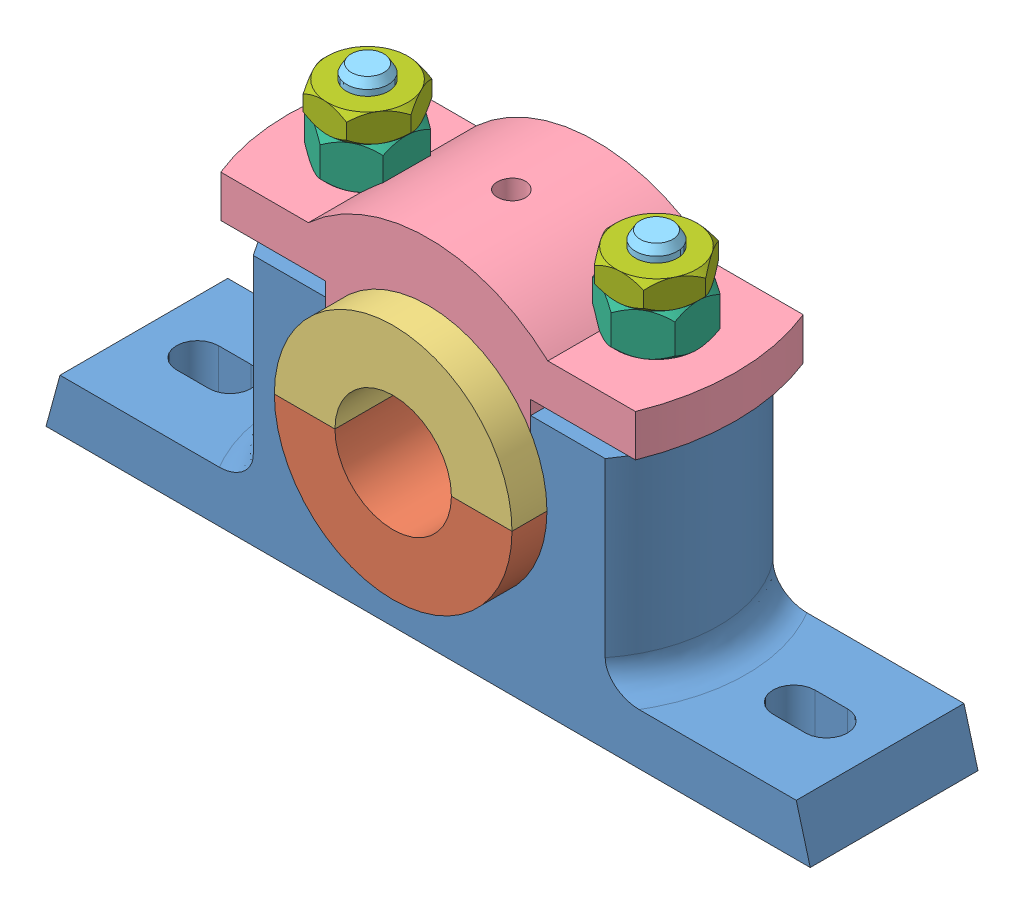
SolidWorks assembly Assem1, configuration Default. Lengths in mm.
Overall size (164 84 51).
10 component instances, 7 part files, 13 mates.
Components (placement in the parent):
- Part1-2: Part1 [Default] at (47.1008 133.5822 81.464) size (164 54 36)
- part3 - Copy-4: part3 - Copy [Default] at (47.1008 133.5822 99.464) x (0 -1 0) z (-1 0 0) size (25.5 51 51)
- part3-3: part3 [Default] at (47.1008 133.5822 99.464) x (0 1 0) z (-1 0 0) size (25.5 51 51)
- PART2-3: PART2 [Default] at (47.1008 133.5822 99.464) size (96 32 36)
- bolt-1: bolt [Default] at (16.1008 179.5822 99.464) x (-0.397328 0 0.917677) z (0 -1 0) size (19 19 82)
- nut-1: nut [Default] at (16.1008 166.0822 99.464) x (0.854581 0 0.519317) z (0 1 0) size (21.91 17.25 9)
- nut2-1: nut2 [Default] at (16.1008 170.5822 99.464) x (-0.997947 0 -0.064045) z (0 1 0) size (21.91 17.25 6)
- nut2-2: nut2 [Default] at (78.1008 176.5822 99.464) x (0.997947 0 -0.064045) z (0 -1 0) size (21.91 17.25 6)
- nut-2: nut [Default] at (78.1008 166.0822 99.464) x (-0.854581 0 0.519317) z (0 -1 0) size (21.91 17.25 9)
- bolt-2: bolt [Default] at (78.1008 179.5822 99.4641) x (-0.397328 0 -0.917677) z (0 -1 0) size (19 19 82)
Mates (geometry in assembly coordinates):
- Concentric17: concentric anti-aligned: cylinder of Part1-2 through (47.1008 133.5822 117.464) axis (0 0 -1) radius 19; cylinder of part3 - Copy-4 through (47.1008 133.5822 129.3327) axis (0 0 1) radius 19
- Concentric18: concentric anti-aligned: cylinder of Part1-2 through (47.1008 114.5822 99.464) axis (0 1 0) radius 3; cylinder of part3 - Copy-4 through (47.1008 500133.5822 99.464) axis (0 -1 0) radius 3
- Coincident21: coincident anti-aligned: plane of part3 - Copy-4 through (47.1008 133.5822 99.464) normal (0 1 0); plane of part3-3 through (47.1008 133.5822 99.464) normal (0 -1 0)
- Concentric19: concentric anti-aligned: cylinder of part3 - Copy-4 through (47.1008 133.5822 99.464) axis (0 0 -1) radius 12.5; cylinder of part3-3 through (47.1008 133.5822 99.464) axis (0 0 1) radius 12.5
- Coincident22: coincident aligned: plane of part3 - Copy-4 through (59.6008 133.5822 124.964) normal (0 0 1); plane of part3-3 through (59.6008 133.5822 124.964) normal (0 0 1)
- Concentric20: concentric anti-aligned: cylinder of part3-3 through (47.1008 133.5822 69.5954) axis (0 0 -1) radius 17.5; cylinder of PART2-3 through (47.1008 133.5822 81.464) axis (0 0 1) radius 19
- Coincident23: coincident aligned: plane of Part1-2 through (47.1008 133.5822 117.464) normal (0 0 1); plane of PART2-3 through (47.1008 133.5822 117.464) normal (0 0 1)
- Coincident24: coincident anti-aligned: plane of Part1-2 through (47.1008 103.5822 81.464) normal (0 -1 0); plane of bolt-1 through (16.1008 103.5822 99.464) normal (0 1 0)
- Coincident26: coincident anti-aligned: plane of PART2-3 through (-2.8992 161.5822 81.464) normal (0 1 0); plane of nut-1 through (16.1008 161.5822 99.464) normal (0 -1 0)
- Coincident27: coincident aligned: cylinder of bolt-1 through (16.1008 103.5822 99.464) axis (0 1 0) radius 4.5; circle of nut-1
- Coincident28: coincident anti-aligned: plane of nut-1 through (16.1008 170.5822 99.464) normal (0 1 0); plane of nut2-1 through (16.1008 170.5822 99.464) normal (0 -1 0)
- Coincident29: coincident aligned: cylinder of bolt-1 through (16.1008 103.5822 99.464) axis (0 1 0) radius 4.5; circle of nut2-1
- Screw1: screw = 1 aligned: cylinder of bolt-1 through (16.1008 103.5822 99.464) axis (0 1 0) radius 4.5; circle of nut2-1
